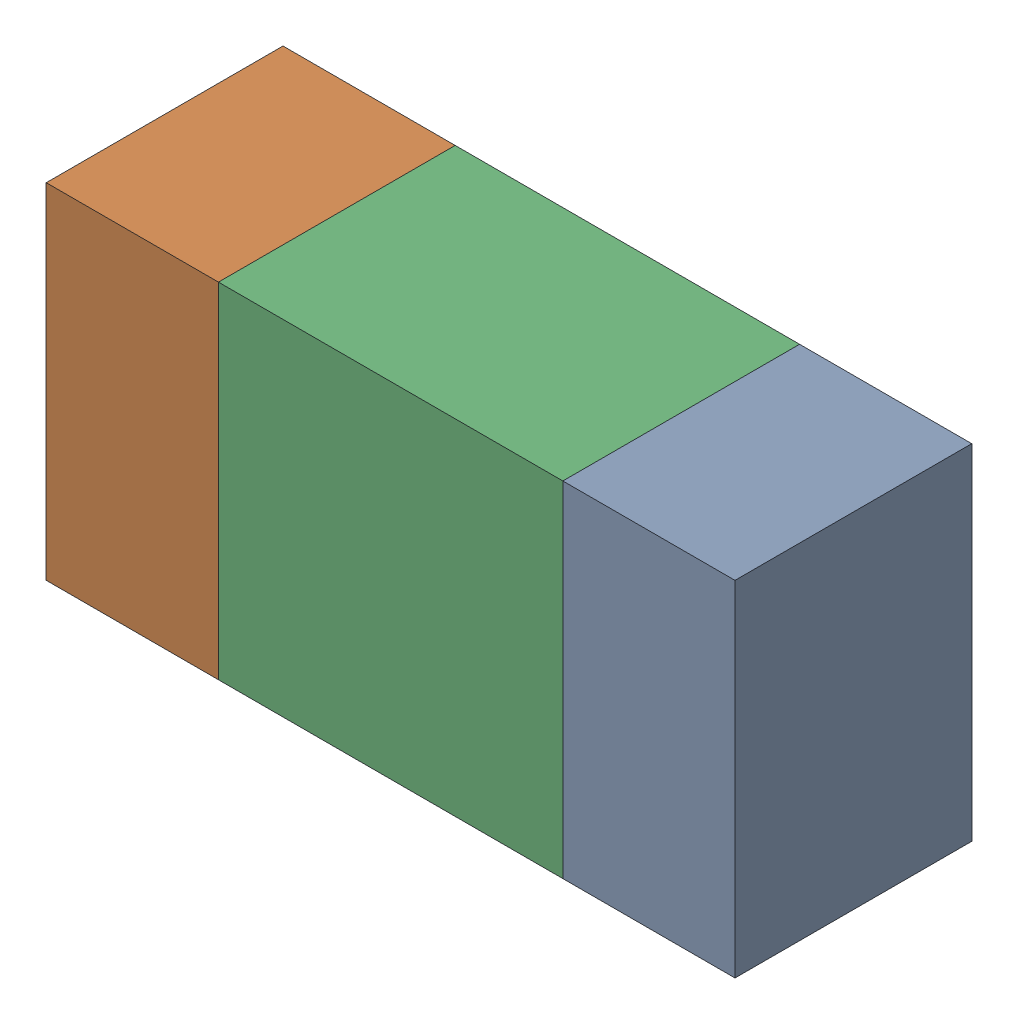
SolidWorks assembly R33, configuration ﾃﾞﾌｫﾙﾄ. Lengths in mm.
Overall size (1.6 0.8 0.55).
6 component instances, 2 part files, 0 mates.
Components (placement in the parent):
- 689261512-1: 689261512 [ﾃﾞﾌｫﾙﾄ] at (6.3149 15.2401 -1.7503) size (0.4 0.8 0.55)
  - Extruded_32-1: Extruded_32 [ﾃﾞﾌｫﾙﾄ] at origin size (0.4 0.8 0.55)
- 689261512-2: 689261512 [ﾃﾞﾌｫﾙﾄ] at (5.1149 15.2401 -1.7503) size (0.4 0.8 0.55)
  - Extruded_32-1: Extruded_32 [ﾃﾞﾌｫﾙﾄ] at origin size (0.4 0.8 0.55)
- 689261648-1: 689261648 [ﾃﾞﾌｫﾙﾄ] at (5.715 15.2401 -1.7503) size (0.8 0.8 0.55)
  - Extruded_33-1: Extruded_33 [ﾃﾞﾌｫﾙﾄ] at origin size (0.8 0.8 0.55)
